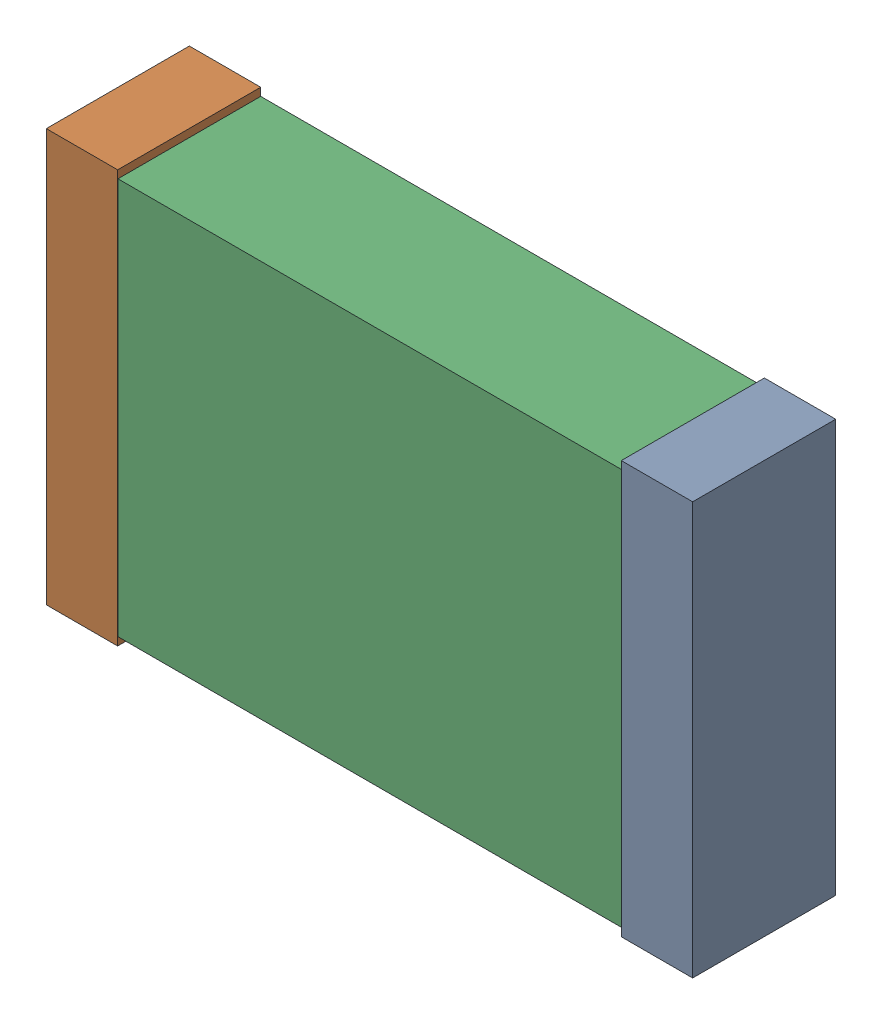
SolidWorks assembly C51, configuration Default. Lengths in mm.
Overall size (2.04 1.3 0.45).
6 component instances, 2 part files, 0 mates.
Components (placement in the parent):
- 870943360-1: 870943360 [Default] at (63.4848 22.2482 0) size (0.23 1.3 0.45)
  - Extruded_40-1: Extruded_40 [Default] at origin size (0.23 1.3 0.45)
- 870943360-2: 870943360 [Default] at (61.6723 22.2482 0) size (0.23 1.3 0.45)
  - Extruded_40-1: Extruded_40 [Default] at origin size (0.23 1.3 0.45)
- 870943200-1: 870943200 [Default] at (62.5848 22.2482 0) size (2 1.25 0.45)
  - Extruded_39-1: Extruded_39 [Default] at origin size (2 1.25 0.45)
